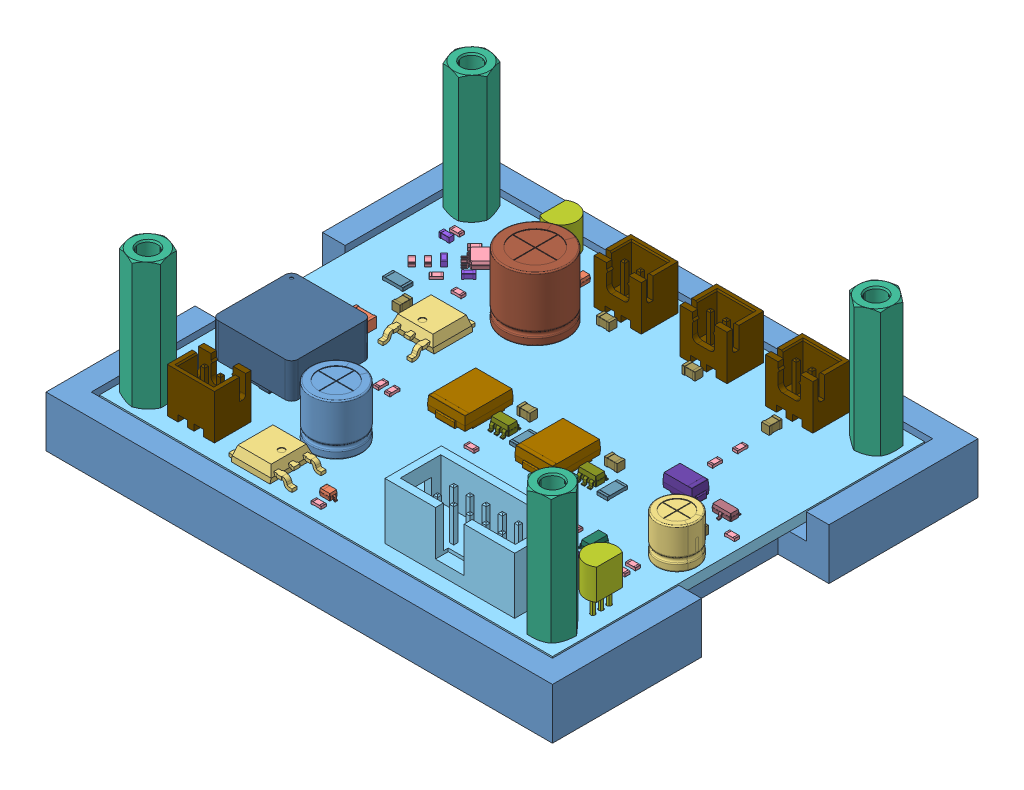
SolidWorks assembly Assem24, configuration Default. Lengths in mm.
Overall size (79.5 27.81 66.8).
141 component instances, 24 part files, 12 mates.
Components (placement in the parent):
- PCB Bracket-1: PCB Bracket [Default] at (-2.2346 -0.9541 -0.8902) size (79.5 8 66.8)
- Power Board V2.step-1: Power Board V2.step [Default] at (-141.9346 5.0459 -105.0302) x (1 0 0) z (0 1 0) size (71.12 58.42 13.45)
  - D_SOD-323.step-1: D_SOD-323.step [Default] at (163.5252 -120.3325 1.65) x (-1 0 0) z (0 0 1) size (2.5 1.25 1.1)
    - SOLID.step-1: SOLID.step [Default] at origin size (2.5 1.25 1.1)
  - TO-252-2.step-1: TO-252-2.step [Default] at (121.666 -99.509 1.65) x (0 1 0) z (0 0 1) size (9.9 6.5 2.32)
    - SOLID-0.step-1: SOLID-0.step [Default] at origin size (9.9 6.5 2.32)
  - R_0603_1608Metric.step-1: R_0603_1608Metric.step [Default] at (169.418 -114.8715 1.65) size (1.6 0.8 0.45)
    - SOLID-1.step-1: SOLID-1.step [Default] at origin size (1.6 0.8 0.45)
  - D_SOD-323.step-2: D_SOD-323.step [Default] at (136.017 -129.286 1.65) size (2.5 1.25 1.1)
    - SOLID.step-1: SOLID.step [Default] at origin size (2.5 1.25 1.1)
  - IDC-Header_2x05_P2.54mm_Vertical.step-1: IDC-Header_2x05_P2.54mm_Vertical.step [Default] at (152.146 -128.27 1.65) x (0 1 0) z (0 0 1) size (9.1 20.36 12.1)
    - SOLID-2.step-1: SOLID-2.step [Default] at origin size (9.1 20.36 12.1)
  - R_0603_1608Metric.step-2: R_0603_1608Metric.step [Default] at (136.398 -131.191 1.65) size (1.6 0.8 0.45)
    - SOLID-1.step-1: SOLID-1.step [Default] at origin size (1.6 0.8 0.45)
  - TO-252-2.step-2: TO-252-2.step [Default] at (127.635 -128.905 1.65) x (-1 0 0) z (0 0 1) size (9.9 6.5 2.32)
    - SOLID-0.step-1: SOLID-0.step [Default] at origin size (9.9 6.5 2.32)
  - R_0603_1608Metric.step-3: R_0603_1608Metric.step [Default] at (118.745 -91.567 1.65) size (1.6 0.8 0.45)
    - SOLID-1.step-1: SOLID-1.step [Default] at origin size (1.6 0.8 0.45)
  - D_SOD-323.step-3: D_SOD-323.step [Default] at (126.873 -80.391 1.65) x (0 1 0) z (0 0 1) size (2.5 1.25 1.1)
    - SOLID.step-1: SOLID.step [Default] at origin size (2.5 1.25 1.1)
  - SOIC-8_3.9x4.9mm_P1.27mm.step-1: SOIC-8_3.9x4.9mm_P1.27mm.step [Default] at (168.275 -102.743 -0.05) x (-1 0 0) z (0 0 -1) size (6 4.9 1.75)
    - SOLID-3.step-1: SOLID-3.step [Default] at origin size (6 4.9 1.75)
  - R_0603_1608Metric.step-4: R_0603_1608Metric.step [Default] at (169.418 -116.5225 1.65) x (-1 0 0) z (0 0 1) size (1.6 0.8 0.45)
    - SOLID-1.step-1: SOLID-1.step [Default] at origin size (1.6 0.8 0.45)
  - TO-92_Inline.step-1: TO-92_Inline.step [Default] at (122.936 -78.359 1.65) x (0 -1 0) z (0 0 1) size (4.83 3.75 9.8)
    - SOLID-4.step-1: SOLID-4.step [Default] at origin size (4.83 3.75 9.8)
  - R_0603_1608Metric.step-5: R_0603_1608Metric.step [Default] at (119.634 -86.0298 1.65) x (-0.707107 -0.707107 0) z (0 0 1) size (1.6 0.8 0.45)
    - SOLID-1.step-1: SOLID-1.step [Default] at origin size (1.6 0.8 0.45)
  - R_0603_1608Metric.step-6: R_0603_1608Metric.step [Default] at (119.888 -78.486 1.65) x (0 1 0) z (0 0 1) size (1.6 0.8 0.45)
    - SOLID-1.step-1: SOLID-1.step [Default] at origin size (1.6 0.8 0.45)
  - C_0603_1608Metric.step-1: C_0603_1608Metric.step [Default] at (110.236 -84.963 1.65) size (1.6 0.8 0.8)
    - SOLID-5.step-1: SOLID-5.step [Default] at origin size (1.6 0.8 0.8)
  - R_0603_1608Metric.step-7: R_0603_1608Metric.step [Default] at (110.744 -90.932 1.65) x (-0.707107 0.707107 0) z (0 0 1) size (1.6 0.8 0.45)
    - SOLID-1.step-1: SOLID-1.step [Default] at origin size (1.6 0.8 0.45)
  - D_SMC.step-1: D_SMC.step [Default] at (135.1915 -106.172 1.65) x (0 1 0) z (0 0 1) size (8 5.9 2.31)
    - SOLID-6.step-1: SOLID-6.step [Default] at origin size (8 5.9 2.31)
  - D_SMC.step-2: D_SMC.step [Default] at (148.9075 -106.172 1.65) x (0 1 0) z (0 0 1) size (8 5.9 2.31)
    - SOLID-6.step-1: SOLID-6.step [Default] at origin size (8 5.9 2.31)
  - L_Bourns_SRF1260.step-1: L_Bourns_SRF1260.step [Default] at (114.8715 -113.919 1.65) size (12.5 12.5 6.2)
    - SOLID-7.step-1: SOLID-7.step [Default] at origin size (12.5 12.5 6.2)
  - CP_Radial_D10.0mm_P5.00mm.step-1: CP_Radial_D10.0mm_P5.00mm.step [Default] at (128.27 -91.567 1.65) x (0 1 0) z (0 0 1) size (12.36 12.78 12)
    - SOLID-8.step-1: SOLID-8.step [Default] at origin size (12.36 12.78 12)
  - R_0603_1608Metric.step-8: R_0603_1608Metric.step [Default] at (120.904 -87.2998 1.65) x (0.707107 0.707107 0) z (0 0 1) size (1.6 0.8 0.45)
    - SOLID-1.step-1: SOLID-1.step [Default] at origin size (1.6 0.8 0.45)
  - C_0603_1608Metric.step-2: C_0603_1608Metric.step [Default] at (117.221 -77.47 1.65) x (-1 0 0) z (0 0 1) size (1.6 0.8 0.8)
    - SOLID-5.step-1: SOLID-5.step [Default] at origin size (1.6 0.8 0.8)
  - C_0603_1608Metric.step-3: C_0603_1608Metric.step [Default] at (117.221 -79.375 1.65) x (-1 0 0) z (0 0 1) size (1.6 0.8 0.8)
    - SOLID-5.step-1: SOLID-5.step [Default] at origin size (1.6 0.8 0.8)
  - C_0603_1608Metric.step-4: C_0603_1608Metric.step [Default] at (117.221 -88.4555 1.65) x (0.707107 0.707107 0) z (0 0 1) size (1.6 0.8 0.8)
    - SOLID-5.step-1: SOLID-5.step [Default] at origin size (1.6 0.8 0.8)
  - C_0603_1608Metric.step-5: C_0603_1608Metric.step [Default] at (113.284 -88.392 1.65) x (-0.707107 0.707107 0) z (0 0 1) size (1.6 0.8 0.8)
    - SOLID-5.step-1: SOLID-5.step [Default] at origin size (1.6 0.8 0.8)
  - C_0805_2012Metric.step-1: C_0805_2012Metric.step [Default] at (116.205 -97.8535 1.65) x (0 1 0) z (0 0 1) size (2 1.25 1.25)
    - SOLID-9.step-1: SOLID-9.step [Default] at origin size (2 1.25 1.25)
  - C_0805_2012Metric.step-2: C_0805_2012Metric.step [Default] at (159.512 -116.205 1.65) x (-1 0 0) z (0 0 1) size (2 1.25 1.25)
    - SOLID-9.step-1: SOLID-9.step [Default] at origin size (2 1.25 1.25)
  - C_0805_2012Metric.step-3: C_0805_2012Metric.step [Default] at (169.926 -105.156 1.65) size (2 1.25 1.25)
    - SOLID-9.step-1: SOLID-9.step [Default] at origin size (2 1.25 1.25)
  - C_0805_2012Metric.step-4: C_0805_2012Metric.step [Default] at (140.716 -102.743 1.65) size (2 1.25 1.25)
    - SOLID-9.step-1: SOLID-9.step [Default] at origin size (2 1.25 1.25)
  - C_0805_2012Metric.step-5: C_0805_2012Metric.step [Default] at (134.62 -84.201 1.65) x (-1 0 0) z (0 0 1) size (2 1.25 1.25)
    - SOLID-9.step-1: SOLID-9.step [Default] at origin size (2 1.25 1.25)
  - C_0805_2012Metric.step-6: C_0805_2012Metric.step [Default] at (154.432 -102.743 1.65) size (2 1.25 1.25)
    - SOLID-9.step-1: SOLID-9.step [Default] at origin size (2 1.25 1.25)
  - C_0805_2012Metric.step-7: C_0805_2012Metric.step [Default] at (148.082 -84.201 1.65) x (-1 0 0) z (0 0 1) size (2 1.25 1.25)
    - SOLID-9.step-1: SOLID-9.step [Default] at origin size (2 1.25 1.25)
  - TO-92_Inline.step-2: TO-92_Inline.step [Default] at (172.593 -124.333 1.65) x (0 1 0) z (0 0 1) size (4.83 3.75 9.8)
    - SOLID-4.step-1: SOLID-4.step [Default] at origin size (4.83 3.75 9.8)
  - SOT-23.step-1: SOT-23.step [Default] at (169.672 -100.584 1.65) x (0 -1 0) z (0 0 1) size (2.5 3 1.2)
    - SOLID-10.step-1: SOLID-10.step [Default] at origin size (2.5 3 1.2)
  - R_1206_3216Metric.step-1: R_1206_3216Metric.step [Default] at (112.395 -94.742 1.65) size (3.2 1.6 0.55)
    - SOLID-11.step-1: SOLID-11.step [Default] at origin size (3.2 1.6 0.55)
  - R_0603_1608Metric.step-9: R_0603_1608Metric.step [Default] at (169.418 -118.1735 1.65) size (1.6 0.8 0.45)
    - SOLID-1.step-1: SOLID-1.step [Default] at origin size (1.6 0.8 0.45)
  - R_0603_1608Metric.step-10: R_0603_1608Metric.step [Default] at (140.7795 -111.5695 1.65) x (-1 0 0) z (0 0 1) size (1.6 0.8 0.45)
    - SOLID-1.step-1: SOLID-1.step [Default] at origin size (1.6 0.8 0.45)
  - R_0603_1608Metric.step-11: R_0603_1608Metric.step [Default] at (173.228 -103.124 1.65) size (1.6 0.8 0.45)
    - SOLID-1.step-1: SOLID-1.step [Default] at origin size (1.6 0.8 0.45)
  - R_0603_1608Metric.step-12: R_0603_1608Metric.step [Default] at (161.925 -90.551 1.65) x (0 -1 0) z (0 0 1) size (1.6 0.8 0.45)
    - SOLID-1.step-1: SOLID-1.step [Default] at origin size (1.6 0.8 0.45)
  - R_0603_1608Metric.step-13: R_0603_1608Metric.step [Default] at (161.925 -94.488 1.65) x (0 1 0) z (0 0 1) size (1.6 0.8 0.45)
    - SOLID-1.step-1: SOLID-1.step [Default] at origin size (1.6 0.8 0.45)
  - R_0603_1608Metric.step-14: R_0603_1608Metric.step [Default] at (154.4955 -111.633 1.65) x (-1 0 0) z (0 0 1) size (1.6 0.8 0.45)
    - SOLID-1.step-1: SOLID-1.step [Default] at origin size (1.6 0.8 0.45)
  - SOT-23-6.step-1: SOT-23-6.step [Default] at (163.957 -115.443 1.65) x (-1 0 0) z (0 0 1) size (2.8 2.9 1.55)
    - SOLID-12.step-1: SOLID-12.step [Default] at origin size (2.8 2.9 1.55)
  - SOT-23-5.step-1: SOT-23-5.step [Default] at (140.716 -106.3625 1.65) x (0 1 0) z (0 0 1) size (2.8 2.9 1.55)
    - SOLID-13.step-1: SOLID-13.step [Default] at origin size (2.8 2.9 1.55)
  - SOT-23-5.step-2: SOT-23-5.step [Default] at (154.432 -106.3625 1.65) x (0 1 0) z (0 0 1) size (2.8 2.9 1.55)
    - SOLID-13.step-1: SOLID-13.step [Default] at origin size (2.8 2.9 1.55)
  - C_0805_2012Metric.step-8: C_0805_2012Metric.step [Default] at (114.935 -123.317 1.65) x (-1 0 0) z (0 0 1) size (2 1.25 1.25)
    - SOLID-9.step-1: SOLID-9.step [Default] at origin size (2 1.25 1.25)
  - R_0603_1608Metric.step-15: R_0603_1608Metric.step [Default] at (123.317 -115.824 1.65) size (1.6 0.8 0.45)
    - SOLID-1.step-1: SOLID-1.step [Default] at origin size (1.6 0.8 0.45)
  - R_0603_1608Metric.step-16: R_0603_1608Metric.step [Default] at (123.317 -114.046 1.65) x (-1 0 0) z (0 0 1) size (1.6 0.8 0.45)
    - SOLID-1.step-1: SOLID-1.step [Default] at origin size (1.6 0.8 0.45)
  - R_0603_1608Metric.step-17: R_0603_1608Metric.step [Default] at (126.873 -110.109 1.65) x (0 -1 0) z (0 0 1) size (1.6 0.8 0.45)
    - SOLID-1.step-1: SOLID-1.step [Default] at origin size (1.6 0.8 0.45)
  - R_0603_1608Metric.step-18: R_0603_1608Metric.step [Default] at (125.095 -110.123 1.65) x (0 1 0) z (0 0 1) size (1.6 0.8 0.45)
    - SOLID-1.step-1: SOLID-1.step [Default] at origin size (1.6 0.8 0.45)
  - D_SMA.step-1: D_SMA.step [Default] at (163.449 -100.584 1.65) x (-1 0 0) z (0 0 1) size (5 2.7 2.22)
    - SOLID-14.step-1: SOLID-14.step [Default] at origin size (5 2.7 2.22)
  - JST_XH_B2B-XH-A_1x02_P2.50mm_Vertical.step-1: JST_XH_B2B-XH-A_1x02_P2.50mm_Vertical.step [Default] at (114.808 -127.508 1.65) size (7.4 5.75 10.4)
    - SOLID-15.step-1: SOLID-15.step [Default] at origin size (7.4 5.75 10.4)
  - JST_XH_B2B-XH-A_1x02_P2.50mm_Vertical.step-2: JST_XH_B2B-XH-A_1x02_P2.50mm_Vertical.step [Default] at (136.017 -80.264 1.65) x (-1 0 0) z (0 0 1) size (7.4 5.75 10.4)
    - SOLID-15.step-1: SOLID-15.step [Default] at origin size (7.4 5.75 10.4)
  - JST_XH_B2B-XH-A_1x02_P2.50mm_Vertical.step-3: JST_XH_B2B-XH-A_1x02_P2.50mm_Vertical.step [Default] at (149.479 -80.264 1.65) x (-1 0 0) z (0 0 1) size (7.4 5.75 10.4)
    - SOLID-15.step-1: SOLID-15.step [Default] at origin size (7.4 5.75 10.4)
  - JST_XH_B2B-XH-A_1x02_P2.50mm_Vertical.step-4: JST_XH_B2B-XH-A_1x02_P2.50mm_Vertical.step [Default] at (162.941 -80.264 1.65) x (-1 0 0) z (0 0 1) size (7.4 5.75 10.4)
    - SOLID-15.step-1: SOLID-15.step [Default] at origin size (7.4 5.75 10.4)
  - R_0603_1608Metric.step-19: R_0603_1608Metric.step [Default] at (159.766 -114.3 1.65) size (1.6 0.8 0.45)
    - SOLID-1.step-1: SOLID-1.step [Default] at origin size (1.6 0.8 0.45)
  - CP_Radial_D8.0mm_P3.50mm.step-1: CP_Radial_D8.0mm_P3.50mm.step [Default] at (128.778 -122.555 1.65) x (0 1 0) z (0 0 1) size (9.82 10.23 10)
    - SOLID-16.step-1: SOLID-16.step [Default] at origin size (9.82 10.23 10)
  - R_0603_1608Metric.step-20: R_0603_1608Metric.step [Default] at (114.681 -90.9955 1.65) x (0.707107 0.707107 0) z (0 0 1) size (1.6 0.8 0.45)
    - SOLID-1.step-1: SOLID-1.step [Default] at origin size (1.6 0.8 0.45)
  - C_0603_1608Metric.step-6: C_0603_1608Metric.step [Default] at (163.195 -118.237 1.65) x (-1 0 0) z (0 0 1) size (1.6 0.8 0.8)
    - SOLID-5.step-1: SOLID-5.step [Default] at origin size (1.6 0.8 0.8)
  - C_0805_2012Metric.step-9: C_0805_2012Metric.step [Default] at (161.671 -85.344 1.65) x (0 -1 0) z (0 0 1) size (2 1.25 1.25)
    - SOLID-9.step-1: SOLID-9.step [Default] at origin size (2 1.25 1.25)
  - R_1206_3216Metric.step-2: R_1206_3216Metric.step [Default] at (143.9545 -106.3625 1.65) x (0 -1 0) z (0 0 1) size (3.2 1.6 0.55)
    - SOLID-11.step-1: SOLID-11.step [Default] at origin size (3.2 1.6 0.55)
  - R_1206_3216Metric.step-3: R_1206_3216Metric.step [Default] at (157.6832 -106.3625 1.65) x (0 -1 0) z (0 0 1) size (3.2 1.6 0.55)
    - SOLID-11.step-1: SOLID-11.step [Default] at origin size (3.2 1.6 0.55)
  - R_0603_1608Metric.step-21: R_0603_1608Metric.step [Default] at (112.014 -89.662 1.65) x (-0.707107 0.707107 0) z (0 0 1) size (1.6 0.8 0.45)
    - SOLID-1.step-1: SOLID-1.step [Default] at origin size (1.6 0.8 0.45)
  - R_0603_1608Metric.step-22: R_0603_1608Metric.step [Default] at (110.236 -83.312 1.65) size (1.6 0.8 0.45)
    - SOLID-1.step-1: SOLID-1.step [Default] at origin size (1.6 0.8 0.45)
  - R_0603_1608Metric.step-23: R_0603_1608Metric.step [Default] at (113.792 -84.074 1.65) x (0.707107 0.707107 0) z (0 0 1) size (1.6 0.8 0.45)
    - SOLID-1.step-1: SOLID-1.step [Default] at origin size (1.6 0.8 0.45)
  - C_1206_3216Metric.step-1: C_1206_3216Metric.step [Default] at (115.2525 -103.3272 1.65) size (3.2 1.6 1.6)
    - SOLID-17.step-1: SOLID-17.step [Default] at origin size (3.2 1.6 1.6)
  - CP_Radial_D6.3mm_P2.50mm.step-1: CP_Radial_D6.3mm_P2.50mm.step [Default] at (170.18 -109.982 1.65) size (7.78 8.05 8.3)
    - SOLID-18.step-1: SOLID-18.step [Default] at origin size (7.78 8.05 8.3)
  - VSSOP-10_3x3mm_P0.5mm.step-1: VSSOP-10_3x3mm_P0.5mm.step [Default] at (116.332 -85.344 1.65) x (-0.707107 -0.707107 0) z (0 0 1) size (4.9 3 1.2)
    - SOLID-19.step-1: SOLID-19.step [Default] at origin size (4.9 3 1.2)
  - COMPOUND.step-1: COMPOUND.step [Default] at origin size (71.12 58.42 1.6)
- hexagonal_spacer_MF_M3_H20_HEX5.5_FTD6_MTL6.step-1: hexagonal_spacer_MF_M3_H20_HEX5.5_FTD6_MTL6.step [Default] at (-33.9846 6.6459 -26.2902) x (-0.308184 0 -0.951327) z (0 1 0) size (6.36 5.51 26.21)
- hexagonal_spacer_MF_M3_H20_HEX5.5_FTD6_MTL6.step-2: hexagonal_spacer_MF_M3_H20_HEX5.5_FTD6_MTL6.step [Default] at (29.5154 6.6459 -26.2902) x (0.809863 0 0.586619) z (0 1 0) size (6.36 5.51 26.21)
- hexagonal_spacer_MF_M3_H20_HEX5.5_FTD6_MTL6.step-3: hexagonal_spacer_MF_M3_H20_HEX5.5_FTD6_MTL6.step [Default] at (29.5154 6.6459 24.5098) x (0.303083 0 -0.952964) z (0 1 0) size (6.36 5.51 26.21)
- hexagonal_spacer_MF_M3_H20_HEX5.5_FTD6_MTL6.step-4: hexagonal_spacer_MF_M3_H20_HEX5.5_FTD6_MTL6.step [Default] at (-33.9846 6.6459 24.5098) x (0.944695 0 0.327951) z (0 1 0) size (6.36 5.51 26.21)
Mates (geometry in assembly coordinates):
- Parallel1: parallel anti-aligned: plane of PCB Bracket-1 through (-2.2346 3.0459 -0.8902) normal (0 1 0); plane of Power Board V2.step-1/COMPOUND.step-1 through (-2.2346 5.0459 -0.8902) normal (0 -1 0)
- Concentric1: concentric anti-aligned: cylinder of PCB Bracket-1 through (29.5154 5.0459 24.5098) axis (0 -1 0) radius 1.75; cylinder of Power Board V2.step-1/COMPOUND.step-1 through (29.5154 4.2459 24.5098) axis (0 1 0) radius 1.6
- Concentric2: concentric anti-aligned: cylinder of PCB Bracket-1 through (-33.9846 5.0459 -26.2902) axis (0 -1 0) radius 1.75; cylinder of Power Board V2.step-1/COMPOUND.step-1 through (-33.9846 4.2459 -26.2902) axis (0 1 0) radius 1.6
- Coincident2: coincident anti-aligned: plane of PCB Bracket-1 through (-2.2346 5.0459 -0.8902) normal (0 1 0); plane of Power Board V2.step-1/COMPOUND.step-1 through (-2.2346 5.0459 -0.8902) normal (0 -1 0)
- Concentric4: concentric aligned: circle of Power Board V2.step-1/COMPOUND.step-1; circle of hexagonal_spacer_MF_M3_H20_HEX5.5_FTD6_MTL6.step-1
- Coincident5: coincident anti-aligned: plane of Power Board V2.step-1/COMPOUND.step-1 through (-2.2346 6.6459 -0.8902) normal (0 1 0); plane of hexagonal_spacer_MF_M3_H20_HEX5.5_FTD6_MTL6.step-1 through (-33.9846 6.6459 -26.2902) normal (0 -1 0)
- Concentric5: concentric: circle of Power Board V2.step-1/COMPOUND.step-1; circle of hexagonal_spacer_MF_M3_H20_HEX5.5_FTD6_MTL6.step-4
- Concentric6: concentric: cylinder of Power Board V2.step-1/COMPOUND.step-1 through (29.5154 4.2459 24.5098) axis (0 1 0) radius 1.6; circle of hexagonal_spacer_MF_M3_H20_HEX5.5_FTD6_MTL6.step-3
- Concentric7: concentric: cylinder of Power Board V2.step-1/COMPOUND.step-1 through (29.5154 4.2459 -26.2902) axis (0 1 0) radius 1.6; circle of hexagonal_spacer_MF_M3_H20_HEX5.5_FTD6_MTL6.step-2
- Coincident6: coincident anti-aligned: plane of Power Board V2.step-1/COMPOUND.step-1 through (-2.2346 6.6459 -0.8902) normal (0 1 0); plane of hexagonal_spacer_MF_M3_H20_HEX5.5_FTD6_MTL6.step-4 through (-33.9846 6.6459 24.5098) normal (0 -1 0)
- Coincident7: coincident anti-aligned: plane of Power Board V2.step-1/COMPOUND.step-1 through (-2.2346 6.6459 -0.8902) normal (0 1 0); plane of hexagonal_spacer_MF_M3_H20_HEX5.5_FTD6_MTL6.step-3 through (29.5154 6.6459 24.5098) normal (0 -1 0)
- Coincident8: coincident anti-aligned: plane of Power Board V2.step-1/COMPOUND.step-1 through (-2.2346 6.6459 -0.8902) normal (0 1 0); plane of hexagonal_spacer_MF_M3_H20_HEX5.5_FTD6_MTL6.step-2 through (29.5154 6.6459 -26.2902) normal (0 -1 0)
